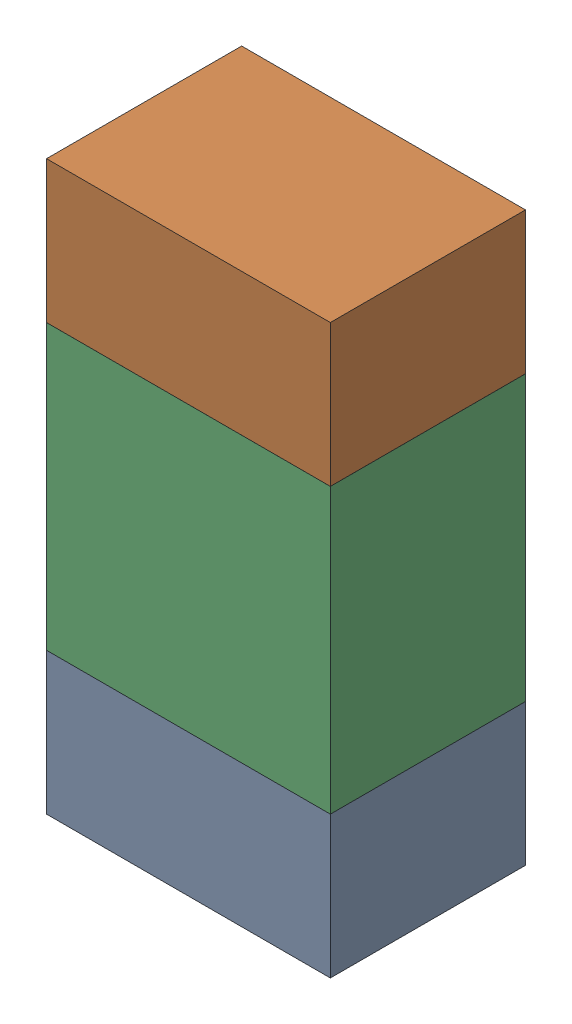
SolidWorks assembly R83, configuration ﾃﾞﾌｫﾙﾄ. Lengths in mm.
Overall size (0.8 1.6 0.55).
6 component instances, 2 part files, 0 mates.
Components (placement in the parent):
- 689261784-1: 689261784 [ﾃﾞﾌｫﾙﾄ] at (39.9999 64.4001 0) size (0.8 0.4 0.55)
  - Extruded_34-1: Extruded_34 [ﾃﾞﾌｫﾙﾄ] at origin size (0.8 0.4 0.55)
- 689261784-2: 689261784 [ﾃﾞﾌｫﾙﾄ] at (39.9999 65.6001 0) size (0.8 0.4 0.55)
  - Extruded_34-1: Extruded_34 [ﾃﾞﾌｫﾙﾄ] at origin size (0.8 0.4 0.55)
- 689261648-1: 689261648 [ﾃﾞﾌｫﾙﾄ] at (39.9999 65 0) size (0.8 0.8 0.55)
  - Extruded_33-1: Extruded_33 [ﾃﾞﾌｫﾙﾄ] at origin size (0.8 0.8 0.55)
